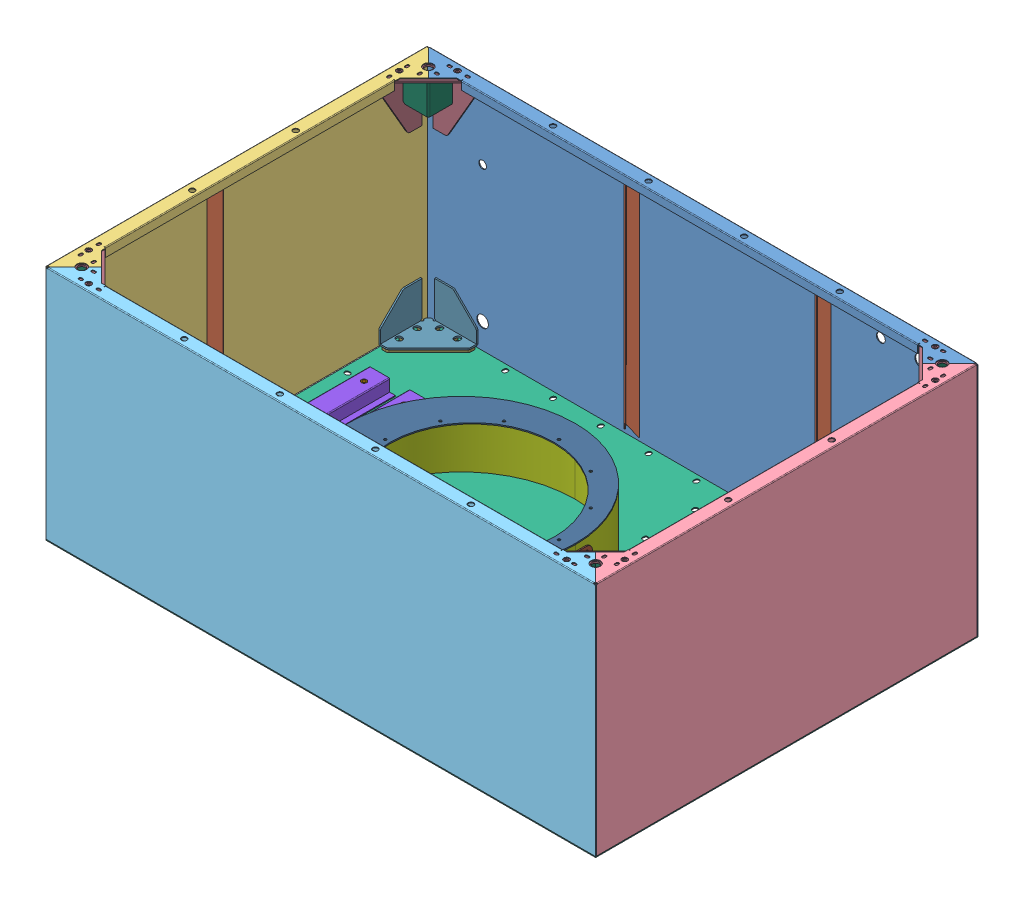
SolidWorks assembly 馬達罩, configuration 預設. Lengths in mm.
Overall size (1414.11 662.5 1048.81).
43 component instances, 17 part files, 56 mates.
Components (placement in the parent):
- LB-A54A-02-18-1: LB-A54A-02-18 [預設] at (-93802.3964 24265.2291 -35.896) size (1380 592.4 69.79)
- LB-A54A-02-36-1: LB-A54A-02-36 [預設] at (15862.5362 -101284.5455 -18772.2864) x (0 1 0) z (-0.760138 0 -0.649762) size (580.6 25.51 29.5)
- LB-A54A-02-36-2: LB-A54A-02-36 [預設] at (16342.5362 -101284.5455 -18772.2864) x (0 1 0) z (-0.760138 0 -0.649762) size (580.6 25.51 29.5)
- 機體上罩-左-1: 機體上罩-左 [預設] at (-656.1377 40.6588 392.6664) x (0 0 -1) z (1 0 0) size (956 658.2 87.66)
  - LB-A54A-02-19-1: LB-A54A-02-19 [預設] at (-96517.3571 24186.4948 -35.896) size (956 658.2 71.79)
  - LB-A54A-02-36-1: LB-A54A-02-36 [預設] at (15928.967 -101325.2043 -18772.2864) x (0 1 0) z (-0.760138 0 -0.649762) size (580.6 25.51 29.5)
- 機體上罩-右-1: 機體上罩-右 [預設] at (654.4533 20.0583 459.454) x (0 0 1) z (-1 0 0) size (956 592.4 85.65)
  - LB-A54A-02-35-1: LB-A54A-02-35 [預設] at (-99028.6914 24183.0457 -35.896) size (956 592.4 69.79)
  - LB-A54A-02-36-1: LB-A54A-02-36 [預設] at (16089.0014 -101304.6038 -18772.2864) x (0 1 0) z (-0.760138 0 -0.649762) size (580.6 25.51 29.5)
- 機體上罩-前-1: 機體上罩-前 [預設] at (-5.5186 -1.8235 888.59) x (-1 0 0) z (0 0 -1) size (1380 592.4 142.36)
  - LB-A54A-02-17-1: LB-A54A-02-17 [預設] at (-91056.5225 24265.1424 -35.896) size (1380 592.4 69.79)
  - LB-A54A-02-36-1: LB-A54A-02-36 [預設] at (15856.7011 -101282.722 -18772.2864) x (0 1 0) z (-0.760138 0 -0.649762) size (580.6 25.51 29.5)
  - LB-A54A-02-36-2: LB-A54A-02-36 [預設] at (16329.3835 -101282.722 -18772.2864) x (0 1 0) z (-0.760138 0 -0.649762) size (580.6 25.51 29.5)
  - 釘雙座-1: 釘雙座 [預設] at (-2.9806 -81.2668 -62.5795) x (0 -1 0) z (0 0 -1) size (19.4 93 19.4)
    - 門蓋丁雙固定座-1: 門蓋丁雙固定座 [預設] at (-112.9585 -46.1037 23.6835) (suppressed, hidden)
    - 釘雙-1: 釘雙 [預設] at (-19.1747 49.3962 36.1835) x (0.021323 0 -0.999773) z (0 -1 0) size (19 19 93)
- 機體蓋板-1: 機體蓋板 [預設] at (58.1777 -318.215 454.3328) x (1 0 0) z (0 1 0) size (1380 960 200.8)
  - LB-A54A-02-15-1: LB-A54A-02-15 [預設] at (-80564.8193 24112.8125 -1.15) size (1380 960 2.3)
  - LB-A54A-02-16-1: LB-A54A-02-16 [預設] at (-8548.809 -14976.4778 1.15) size (600 601 160)
  - LB-A54-08-2-1: LB-A54-08-2 [預設] at (-592.4484 278.8468 34.07) x (0 -1 0) z (0 0 -1) size (278 79.24 32.92)
  - LB-A54-08-2-2: LB-A54-08-2 [預設] at (-492.4484 278.8468 34.07) x (0 -1 0) z (0 0 -1) size (278 79.24 32.92)
  - 2分半點焊螺帽-1: 2分半點焊螺帽 [預設] at (-659.4484 239.8477 26.57) x (0.122877 -0.992422 0) z (-0.992422 -0.122877 0) size (18.22 7.93 18.22)
  - 2分半點焊螺帽-2: 2分半點焊螺帽 [預設] at (-659.4484 39.8477 26.57) x (0.122877 -0.992422 0) z (-0.992422 -0.122877 0) size (18.22 7.93 18.22)
  - 2分半點焊螺帽-3: 2分半點焊螺帽 [預設] at (-559.4484 239.8477 26.57) x (1 0 0) z (0 -1 0) size (18.22 7.93 18.22)
  - 2分半點焊螺帽-4: 2分半點焊螺帽 [預設] at (-559.4484 39.8477 26.57) x (1 0 0) z (0 -1 0) size (18.22 7.93 18.22)
  - LB-A54-08-3-1: LB-A54-08-3 [預設] at (-458.3284 -317.6532 161.15) size (600 601 3)
  - LB-A54-08-9-1: LB-A54-08-9 [預設] at (144.6716 9.3468 1.15) x (0 -1 0) z (-1 0 0) size (365 198.5 3)
  - LB-A54A-02-31-1: LB-A54A-02-31 [預設] at (-111583.8364 25406.8261 1.15) size (117.04 117.04 6)
  - LB-A54A-02-31-2: LB-A54A-02-31 [預設] at (-111583.8364 -25387.1326 7.15) x (1 0 0) z (0 0 -1) size (117.04 117.04 6)
  - LB-A54A-02-31-3: LB-A54A-02-31 [預設] at (25549.151 111325.8547 1.15) x (0 -1 0) z (0 0 1) size (117.04 117.04 6)
  - LB-A54A-02-31-4: LB-A54A-02-31 [預設] at (111468.1796 -25387.1326 1.15) x (-1 0 0) z (0 0 1) size (117.04 117.04 6)
- LB-A54A-02-33-1: LB-A54A-02-33 [預設] at (24045.2002 273.336 106547.9169) x (0 0 -1) z (0 -1 0) size (120.61 124.61 161.4)
- LB-A54A-02-33-2: LB-A54A-02-33 [預設] at (105893.7801 273.336 -23810.7469) x (-1 0 0) z (0 -1 0) size (120.61 124.61 161.4)
- LB-A54A-02-33-3: LB-A54A-02-33 [預設] at (-24044.8837 273.336 -105659.3269) x (0 0 1) z (0 -1 0) size (120.61 124.61 161.4)
- LB-A54A-02-33-4: LB-A54A-02-33 [預設] at (-105893.4636 273.336 24699.3369) x (1 0 0) z (0 -1 0) size (120.61 124.61 161.4)
- LB-A54A-02-34-1: LB-A54A-02-34 [預設] at (-25471.0011 -311.065 108789.6575) x (0 0 -1) z (0 1 0) size (124.6 124.6 94.6)
- LB-A54A-02-34-2: LB-A54A-02-34 [預設] at (-108554.8222 -311.065 -24816.8644) x (1 0 0) z (0 1 0) size (124.6 124.6 94.6)
- LB-A54A-02-34-3: LB-A54A-02-34 [預設] at (108555.5208 -311.065 25705.8364) x (-1 0 0) z (0 1 0) size (124.6 124.6 94.6)
- LB-A54A-02-34-4: LB-A54A-02-34 [預設] at (25471.6997 -311.065 -107900.6855) x (0 0 1) z (0 1 0) size (124.6 124.6 94.6)
- LB-A54-02-5-1: LB-A54-02-5 [預設] at (-683.9417 189.336 854.295) size (64.1 80 64.1)
- LB-A54-02-5-2: LB-A54-02-5 [預設] at (684.2583 269.336 854.295) x (-1 0 0) z (0 0 1) size (64.1 80 64.1)
- LB-A54-02-5-3: LB-A54-02-5 [預設] at (620.1583 269.336 -29.805) x (0 0 1) z (1 0 0) size (64.1 80 64.1)
- LB-A54-02-5-4: LB-A54-02-5 [預設] at (-683.9417 269.336 34.295) x (1 0 0) z (0 0 -1) size (64.1 80 64.1)
Mates (geometry in assembly coordinates):
- 重合/共線/共點1: coincident: plane of LB-A54A-02-18-1 through (645.3715 316.3218 -33.896) normal (0 0 1); line of LB-A54A-02-36-1 through (-157.5608 268.336 -33.896) axis (0 -1 0)
- 重合/共線/共點2: coincident: plane of LB-A54A-02-18-1 through (645.3715 316.3218 -33.896) normal (0 0 1); line of LB-A54A-02-36-1 through (-193.728 -306.664 -33.896) axis (0 1 0)
- 重合/共線/共點3: coincident: line of LB-A54A-02-18-1 through (-199.1458 272.935 -35.896) axis (0 -1 0); plane of LB-A54A-02-36-1 through (-191.2268 268.336 -29.1269) normal (-0.649762 0 0.760138)
- 重合/共線/共點5: coincident anti-aligned: plane of LB-A54A-02-18-1 through (645.3715 273.336 9.0818) normal (0 -1 0); plane of LB-A54A-02-36-1 through (-189.9273 273.336 -30.6472) normal (0 1 0)
- 重合/共線/共點6: coincident: plane of LB-A54A-02-18-1 through (645.3715 316.3218 -33.896) normal (0 0 1); line of LB-A54A-02-36-2 through (322.4392 268.336 -33.896) axis (0 -1 0)
- 重合/共線/共點7: coincident: plane of LB-A54A-02-18-1 through (645.3715 316.3218 -33.896) normal (0 0 1); line of LB-A54A-02-36-2 through (286.272 -306.664 -33.896) axis (0 1 0)
- 重合/共線/共點8: coincident: line of LB-A54A-02-18-1 through (280.8542 272.935 -35.896) axis (0 -1 0); plane of LB-A54A-02-36-2 through (288.7732 268.336 -29.1269) normal (-0.649762 0 0.760138)
- 重合/共線/共點9: coincident anti-aligned: plane of LB-A54A-02-18-1 through (645.3715 273.336 9.0818) normal (0 -1 0); plane of LB-A54A-02-36-2 through (306.1951 273.336 -14.8925) normal (0 1 0)
- 重合/共線/共點10: coincident aligned: plane of LB-A54A-02-18-1 through (645.3715 275.336 9.0818) normal (0 1 0); plane of 機體上罩-左-1/LB-A54A-02-19-1 through (-645.0549 275.336 9.0818) normal (0 1 0)
- 重合/共線/共點11: coincident anti-aligned: plane of LB-A54A-02-18-1 through (-687.5417 273.336 -33.405) normal (-0.707107 0 0.707107); plane of 機體上罩-左-1/LB-A54A-02-19-1 through (-687.5417 273.336 -33.405) normal (0.707107 0 -0.707107)
- 重合/共線/共點12: coincident: point of LB-A54A-02-18-1; line of 機體上罩-左-1/LB-A54A-02-19-1 through (-620.2417 273.336 33.895) axis (0 1 0)
- 重合/共線/共點13: coincident aligned: plane of LB-A54A-02-18-1 through (645.3715 275.336 9.0818) normal (0 1 0); plane of 機體上罩-右-1/LB-A54A-02-35-1 through (645.3715 275.336 9.0818) normal (0 1 0)
- 重合/共線/共點14: coincident anti-aligned: plane of LB-A54A-02-18-1 through (687.8583 273.336 -33.405) normal (0.707107 0 0.707107); plane of 機體上罩-右-1/LB-A54A-02-35-1 through (687.8583 273.336 -33.405) normal (-0.707107 0 -0.707107)
- 重合/共線/共點15: coincident: line of LB-A54A-02-18-1 through (620.5583 273.336 33.895) axis (0 1 0); point of 機體上罩-右-1/LB-A54A-02-35-1
- 重合/共線/共點16: coincident aligned: plane of 機體上罩-右-1/LB-A54A-02-35-1 through (645.3715 275.336 9.0818) normal (0 1 0); plane of 機體上罩-前-1/LB-A54A-02-17-1 through (645.3715 275.336 879.5082) normal (0 1 0)
- 重合/共線/共點17: coincident anti-aligned: plane of 機體上罩-右-1/LB-A54A-02-35-1 through (687.8583 273.336 921.995) normal (-0.707107 0 0.707107); plane of 機體上罩-前-1/LB-A54A-02-17-1 through (687.8583 273.336 921.995) normal (0.707107 0 -0.707107)
- 重合/共線/共點18: coincident: line of 機體上罩-左-1/LB-A54A-02-19-1 through (-620.2417 275.336 854.695) axis (-0.707107 0 0.707107); plane of 機體上罩-前-1/LB-A54A-02-17-1 through (-620.2417 273.336 854.695) normal (-0.707107 0 -0.707107)
- 重合/共線/共點19: coincident anti-aligned: plane of 機體上罩-前-1/LB-A54A-02-17-1 through (-689.8417 -317.065 922.486) normal (0 -1 0); plane of 機體蓋板-1/LB-A54A-02-15-1 through (-689.6507 -317.065 924.486) normal (0 1 0)
- 重合/共線/共點20: coincident aligned: plane of 機體上罩-右-1/LB-A54A-02-35-1 through (690.3493 316.3218 9.0818) normal (1 0 0); plane of 機體蓋板-1/LB-A54A-02-15-1 through (690.3493 -317.065 924.486) normal (1 0 0)
- 重合/共線/共點21: coincident aligned: plane of 機體上罩-前-1/LB-A54A-02-17-1 through (645.3715 316.3218 924.486) normal (0 0 1); plane of 機體蓋板-1/LB-A54A-02-15-1 through (-689.6507 -317.065 924.486) normal (0 0 1)
- 重合/共線/共點22: coincident: line of LB-A54A-02-18-1 through (-584.6417 273.336 -1.705) axis (-0.707107 0 0.707107); plane of LB-A54A-02-33-1 through (-684.4417 273.336 -14.705) normal (0 1 0)
- 同軸心1: concentric aligned: cylinder of 機體上罩-左-1/LB-A54A-02-19-1 through (-645.0549 273.336 9.0818) axis (0 1 0) radius 12; cylinder of LB-A54A-02-33-1 through (-645.0549 269.336 9.0818) axis (0 1 0) radius 9
- 同軸心2: concentric aligned: cylinder of LB-A54A-02-18-1 through (-599.8417 273.336 -18.705) axis (0 1 0) radius 7; cylinder of LB-A54A-02-33-1 through (-599.8417 269.336 -18.705) axis (0 1 0) radius 4.1
- 重合/共線/共點23: coincident anti-aligned: plane of 機體上罩-前-1/LB-A54A-02-17-1 through (645.3715 273.336 879.5082) normal (0 -1 0); plane of LB-A54A-02-33-2 through (-668.8417 273.336 918.895) normal (0 1 0)
- 同軸心3: concentric aligned: cylinder of 機體上罩-左-1/LB-A54A-02-19-1 through (-645.0549 273.336 879.5082) axis (0 1 0) radius 12; cylinder of LB-A54A-02-33-2 through (-645.0549 269.336 879.5082) axis (0 1 0) radius 9
- 同軸心4: concentric aligned: cylinder of 機體上罩-左-1/LB-A54A-02-19-1 through (-672.8417 273.336 834.295) axis (0 1 0) radius 7; cylinder of LB-A54A-02-33-2 through (-672.8417 269.336 834.295) axis (0 1 0) radius 4.1
- 重合/共線/共點24: coincident anti-aligned: plane of 機體上罩-右-1/LB-A54A-02-35-1 through (645.3715 273.336 9.0818) normal (0 -1 0); plane of LB-A54A-02-33-3 through (684.7583 273.336 903.295) normal (0 1 0)
- 同軸心5: concentric aligned: cylinder of 機體上罩-右-1/LB-A54A-02-35-1 through (645.3715 273.336 879.5082) axis (0 1 0) radius 12; cylinder of LB-A54A-02-33-3 through (645.3715 269.336 879.5082) axis (0 1 0) radius 9
- 同軸心6: concentric aligned: cylinder of 機體上罩-右-1/LB-A54A-02-35-1 through (673.1583 273.336 834.295) axis (0 1 0) radius 7; cylinder of LB-A54A-02-33-3 through (673.1583 269.336 834.295) axis (0 1 0) radius 4.1
- 重合/共線/共點25: coincident anti-aligned: plane of LB-A54A-02-33-4 through (669.1583 273.336 -30.305) normal (0 1 0); plane of LB-A54A-02-18-1 through (645.3715 273.336 9.0818) normal (0 -1 0)
- 同軸心7: concentric aligned: cylinder of 機體上罩-右-1/LB-A54A-02-35-1 through (645.3715 273.336 9.0818) axis (0 1 0) radius 12; cylinder of LB-A54A-02-33-4 through (645.3715 269.336 9.0818) axis (0 1 0) radius 9
- 同軸心8: concentric anti-aligned: circle of 機體上罩-右-1/LB-A54A-02-35-1; cylinder of LB-A54A-02-33-4 through (673.1583 269.336 54.295) axis (0 1 0) radius 4.1
- 重合/共線/共點26: coincident anti-aligned: plane of 機體蓋板-1/LB-A54A-02-31-2 through (-571.6507 -311.065 905.7997) normal (0 1 0); plane of LB-A54A-02-34-1 through (-684.2507 -311.065 903.486) normal (0 -1 0)
- 同軸心9: concentric anti-aligned: cylinder of 機體蓋板-1/LB-A54A-02-31-2 through (-644.6507 -317.065 906.4859) axis (0 1 0) radius 7; cylinder of LB-A54A-02-34-1 through (-644.6507 -307.065 906.4859) axis (0 -1 0) radius 7
- 同軸心11: concentric anti-aligned: cylinder of 機體蓋板-1/LB-A54A-02-31-2 through (-599.6507 -317.065 906.4859) axis (0 1 0) radius 7; cylinder of LB-A54A-02-34-1 through (-599.6507 -307.065 906.4859) axis (0 -1 0) radius 7
- 重合/共線/共點27: coincident anti-aligned: plane of 機體蓋板-1/LB-A54A-02-31-1 through (-571.6507 -311.065 -16.8277) normal (0 1 0); plane of LB-A54A-02-34-2 through (-668.6507 -311.065 -30.114) normal (0 -1 0)
- 同軸心12: concentric aligned: cylinder of 機體蓋板-1/LB-A54A-02-31-1 through (-671.6507 -311.065 54.486) axis (0 -1 0) radius 7; cylinder of LB-A54A-02-34-2 through (-671.6507 -307.065 54.486) axis (0 -1 0) radius 7
- 同軸心13: concentric aligned: cylinder of 機體蓋板-1/LB-A54A-02-31-1 through (-671.6507 -311.065 9.486) axis (0 -1 0) radius 7; cylinder of LB-A54A-02-34-2 through (-671.6507 -307.065 9.486) axis (0 -1 0) radius 7
- 重合/共線/共點28: coincident anti-aligned: plane of 機體蓋板-1/LB-A54A-02-31-4 through (572.3493 -311.065 905.7997) normal (0 1 0); plane of LB-A54A-02-34-3 through (669.3493 -311.065 919.086) normal (0 -1 0)
- 同軸心14: concentric aligned: cylinder of 機體蓋板-1/LB-A54A-02-31-4 through (672.3492 -311.065 834.486) axis (0 -1 0) radius 7; cylinder of LB-A54A-02-34-3 through (672.3492 -307.065 834.486) axis (0 -1 0) radius 7
- 同軸心15: concentric aligned: cylinder of 機體蓋板-1/LB-A54A-02-31-4 through (672.3492 -311.065 879.486) axis (0 -1 0) radius 7; cylinder of LB-A54A-02-34-3 through (672.3492 -307.065 879.486) axis (0 -1 0) radius 7
- 重合/共線/共點30: coincident anti-aligned: plane of LB-A54A-02-34-4 through (684.9493 -311.065 -14.514) normal (0 -1 0); plane of 機體蓋板-1/LB-A54A-02-31-3 through (671.663 -311.065 82.486) normal (0 1 0)
- 同軸心16: concentric aligned: cylinder of 機體蓋板-1/LB-A54A-02-31-3 through (672.3492 -311.065 54.486) axis (0 -1 0) radius 7; cylinder of LB-A54A-02-34-4 through (672.3492 -307.065 54.486) axis (0 -1 0) radius 7
- 同軸心17: concentric aligned: cylinder of 機體蓋板-1/LB-A54A-02-31-3 through (672.3492 -311.065 9.486) axis (0 -1 0) radius 7; cylinder of LB-A54A-02-34-4 through (672.3492 -307.065 9.486) axis (0 -1 0) radius 7
- 重合/共線/共點31: coincident anti-aligned: plane of LB-A54A-02-33-2 through (-668.8417 269.336 918.895) normal (0 -1 0); plane of LB-A54-02-5-1 through (-567.7417 269.336 858.295) normal (0 1 0)
- 重合/共線/共點32: coincident: line of LB-A54A-02-33-2 through (-619.8417 273.336 998.895) axis (0 0 -1); plane of LB-A54-02-5-1 through (-619.8417 269.336 797.195) normal (1 0 0)
- 重合/共線/共點34: coincident: line of LB-A54A-02-33-2 through (-621.8417 273.336 854.295) axis (-1 0 0); plane of LB-A54-02-5-1 through (-683.9417 269.336 854.295) normal (0 0 -1)
- 重合/共線/共點36: coincident anti-aligned: plane of LB-A54-02-5-2 through (624.1583 269.336 913.395) normal (0 1 0); plane of LB-A54A-02-33-3 through (684.7583 269.336 903.295) normal (0 -1 0)
- 重合/共線/共點37: coincident: line of LB-A54A-02-33-3 through (764.7583 273.336 854.295) axis (-1 0 0); plane of LB-A54-02-5-2 through (684.2583 189.336 854.295) normal (0 0 -1)
- 重合/共線/共點38: coincident: line of LB-A54A-02-33-3 through (620.1583 273.336 856.295) axis (0 0 1); plane of LB-A54-02-5-2 through (620.1583 189.336 797.195) normal (-1 0 0)
- 重合/共線/共點39: coincident anti-aligned: plane of LB-A54A-02-33-4 through (669.1583 269.336 -30.305) normal (0 -1 0); plane of LB-A54-02-5-3 through (624.1583 269.336 86.395) normal (0 1 0)
- 重合/共線/共點41: coincident: line of LB-A54A-02-33-4 through (620.1583 273.336 -110.305) axis (0 0 1); plane of LB-A54-02-5-3 through (620.1583 189.336 -29.805) normal (-1 0 0)
- 重合/共線/共點42: coincident: line of LB-A54A-02-33-4 through (622.1583 273.336 34.295) axis (1 0 0); plane of LB-A54-02-5-3 through (563.0583 189.336 34.295) normal (0 0 1)
- 重合/共線/共點43: coincident anti-aligned: plane of LB-A54A-02-33-1 through (-684.4417 269.336 -14.705) normal (0 -1 0); plane of LB-A54-02-5-4 through (-623.8417 269.336 -24.805) normal (0 1 0)
- 重合/共線/共點44: coincident: line of LB-A54A-02-33-1 through (-619.8417 273.336 32.295) axis (0 0 -1); plane of LB-A54-02-5-4 through (-619.8417 189.336 91.395) normal (1 0 0)
- 重合/共線/共點45: coincident: line of LB-A54A-02-33-1 through (-764.4417 273.336 34.295) axis (1 0 0); plane of LB-A54-02-5-4 through (-683.9417 189.336 34.295) normal (0 0 1)
